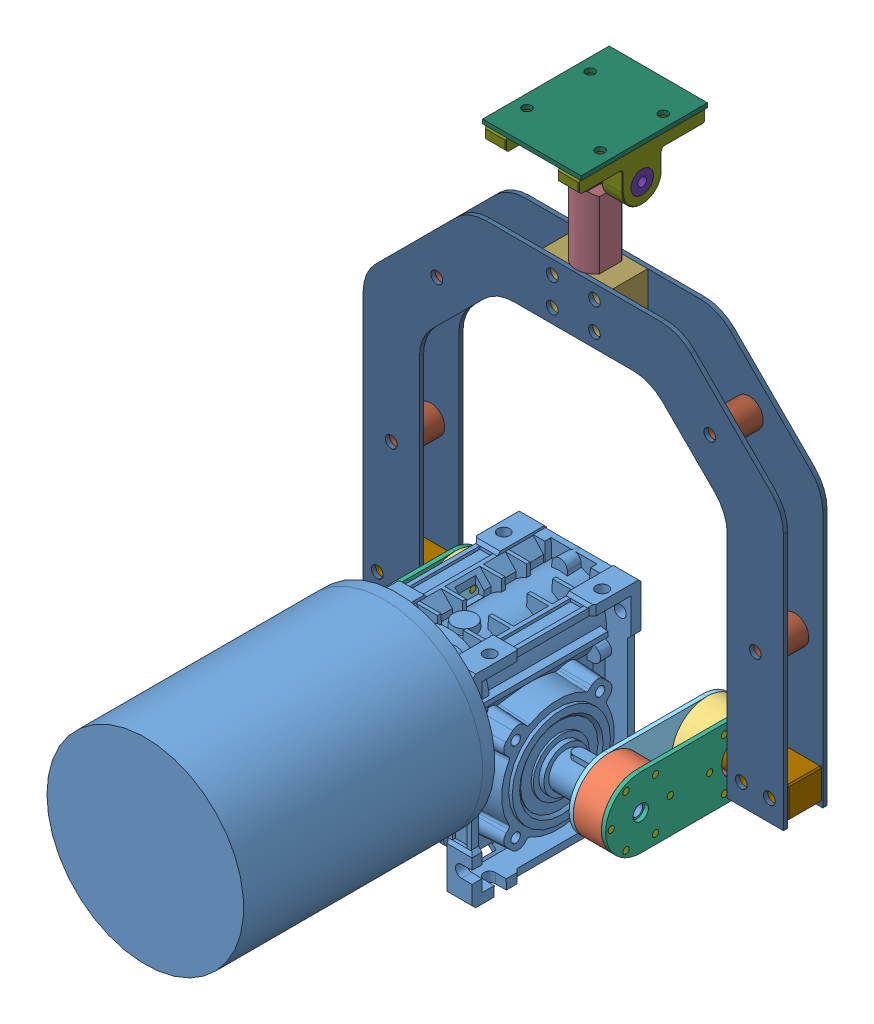
SolidWorks assembly motor con viela, configuration Predeterminado. Lengths in mm.
Overall size (299 406 365).
58 component instances, 18 part files, 42 mates.
Components (placement in the parent):
- reductor con motor-1: reductor con motor [Predeterminado] at origin size (199 179.97 310)
- manivela-1: manivela [Predeterminado] at (79.5 -50 -64) x (0 0 -1) z (1 0 0) size (120 50 26)
  - cople flecha-1: cople flecha [Predeterminado] at origin size (50 50 20)
  - cople rodamiento-1: cople rodamiento [Predeterminado] at (70 0 0) size (50 50 20)
  - rodameitno falso-1: rodameitno falso [Predeterminado] at (70 0 6) size (35 35 14)
  - placa manivela-2: placa manivela [Predeterminado] at (0 0 -3) size (120 50 3)
  - placa manivela 2-3: placa manivela 2 [Predeterminado] at (0 0 20) size (120 50 3)
  - tornillo falso-2: tornillo falso [Predeterminado] at (-10.5 18.1865 23) x (-0.923728 -0.383049 0) z (0 0 -1) size (4.3 4.3 26)
  - tornillo falso-3: tornillo falso [Predeterminado] at (-21 0 23) x (-0.923728 -0.383049 0) z (0 0 -1) size (4.3 4.3 26)
  - tornillo falso-4: tornillo falso [Predeterminado] at (-10.5 -18.1865 23) x (-0.923728 -0.383049 0) z (0 0 -1) size (4.3 4.3 26)
  - tornillo falso-5: tornillo falso [Predeterminado] at (10.5 -18.1865 23) x (-0.923728 -0.383049 0) z (0 0 -1) size (4.3 4.3 26)
  - tornillo falso-6: tornillo falso [Predeterminado] at (21 0 23) x (-0.923728 -0.383049 0) z (0 0 -1) size (4.3 4.3 26)
  - tornillo falso-7: tornillo falso [Predeterminado] at (10.5 18.1865 23) x (-0.923728 -0.383049 0) z (0 0 -1) size (4.3 4.3 26)
  - tornillo falso-8: tornillo falso [Predeterminado] at (59.5 18.1865 23) x (-0.923728 -0.383049 0) z (0 0 -1) size (4.3 4.3 26)
  - tornillo falso-9: tornillo falso [Predeterminado] at (49 0 23) x (-0.923728 -0.383049 0) z (0 0 -1) size (4.3 4.3 26)
  - tornillo falso-10: tornillo falso [Predeterminado] at (80.5 18.1865 23) x (-0.923728 -0.383049 0) z (0 0 -1) size (4.3 4.3 26)
  - tornillo falso-11: tornillo falso [Predeterminado] at (59.5 -18.1865 23) x (-0.923728 -0.383049 0) z (0 0 -1) size (4.3 4.3 26)
  - tornillo falso-12: tornillo falso [Predeterminado] at (80.5 -18.1865 23) x (-0.923728 -0.383049 0) z (0 0 -1) size (4.3 4.3 26)
  - tornillo falso-13: tornillo falso [Predeterminado] at (91 0 23) x (-0.923728 -0.383049 0) z (0 0 -1) size (4.3 4.3 26)
  - anillo manivela-1: anillo manivela [Predeterminado] at (70 0 0) x (0.999916 -0.012929 0) z (0 0 1) size (35 35 6)
- manivela derecha-1: manivela derecha [Predeterminado] at (-99.5 -50 -64) x (0 0 -1) z (1 0 0) size (120 50 26)
  - cople flecha-1: cople flecha [Predeterminado] at origin size (50 50 20)
  - cople rodamiento-1: cople rodamiento [Predeterminado] at (70 0 0) size (50 50 20)
  - rodameitno falso-1: rodameitno falso [Predeterminado] at (70 0 0) size (35 35 14)
  - placa manivela 2-4: placa manivela 2 [Predeterminado] at (0 0 -3) size (120 50 3)
  - placa manivela-3: placa manivela [Predeterminado] at (0 0 20) size (120 50 3)
  - tornillo falso-2: tornillo falso [Predeterminado] at (-10.5 18.1865 23) x (-0.923728 -0.383049 0) z (0 0 -1) size (4.3 4.3 26)
  - tornillo falso-3: tornillo falso [Predeterminado] at (-21 0 23) x (-0.923728 -0.383049 0) z (0 0 -1) size (4.3 4.3 26)
  - tornillo falso-4: tornillo falso [Predeterminado] at (-10.5 -18.1865 23) x (-0.923728 -0.383049 0) z (0 0 -1) size (4.3 4.3 26)
  - tornillo falso-5: tornillo falso [Predeterminado] at (10.5 -18.1865 23) x (-0.923728 -0.383049 0) z (0 0 -1) size (4.3 4.3 26)
  - tornillo falso-6: tornillo falso [Predeterminado] at (21 0 23) x (-0.923728 -0.383049 0) z (0 0 -1) size (4.3 4.3 26)
  - tornillo falso-7: tornillo falso [Predeterminado] at (10.5 18.1865 23) x (-0.923728 -0.383049 0) z (0 0 -1) size (4.3 4.3 26)
  - tornillo falso-8: tornillo falso [Predeterminado] at (59.5 18.1865 23) x (-0.923728 -0.383049 0) z (0 0 -1) size (4.3 4.3 26)
  - tornillo falso-9: tornillo falso [Predeterminado] at (49 0 23) x (-0.923728 -0.383049 0) z (0 0 -1) size (4.3 4.3 26)
  - tornillo falso-10: tornillo falso [Predeterminado] at (80.5 18.1865 23) x (-0.923728 -0.383049 0) z (0 0 -1) size (4.3 4.3 26)
  - tornillo falso-11: tornillo falso [Predeterminado] at (59.5 -18.1865 23) x (-0.923728 -0.383049 0) z (0 0 -1) size (4.3 4.3 26)
  - tornillo falso-12: tornillo falso [Predeterminado] at (80.5 -18.1865 23) x (-0.923728 -0.383049 0) z (0 0 -1) size (4.3 4.3 26)
  - tornillo falso-13: tornillo falso [Predeterminado] at (91 0 23) x (-0.923728 -0.383049 0) z (0 0 -1) size (4.3 4.3 26)
  - anillo manivela-1: anillo manivela [Predeterminado] at (70 0 14) x (0.996967 0.077829 0) z (0 0 1) size (35 35 6)
- pin de manivela-1: pin de manivela [Predeterminado] at (74.5 -50 -134) x (-1 0 0) z (0 0 -1) size (75 22 25)
- pin de manivela-2: pin de manivela [Predeterminado] at (-74.5 -50 -134) size (75 22 25)
- arco-2: arco [Predeterminado] at (0 -65 -149.5) size (299 270 3)
- virlo-1: virlo [Predeterminado] at (129.5 35.125 -146.5) x (-0.745023 -0.667039 0) z (0 0 1) size (20 20 25)
- virlo-2: virlo [Predeterminado] at (-129.5 35.125 -146.5) x (-0.745023 -0.667039 0) z (0 0 1) size (20 20 25)
- virlo-3: virlo [Predeterminado] at (97.125 152.625 -146.5) x (-0.745023 -0.667039 0) z (0 0 1) size (20 20 25)
- virlo-4: virlo [Predeterminado] at (-97.125 152.625 -146.5) x (-0.797624 -0.603155 0) z (0 0 1) size (20 20 25)
- arco-3: arco [Predeterminado] at (0 -65 -121.5) size (299 270 3)
- bloque-1: bloque [Predeterminado] at (0 185 -134) size (50 40 25)
- Rotula de esfera-1: Rotula de esfera [M16] at (0 205 -134) x (0 0 1) z (-1 0 0) size (38 83 22)
  - rotula-1: rotula [M16] at origin size (38 83 22)
  - esfera-1: esfera [M16] at (0 64 0) size (30 30 21)
- soperte superior-1: soperte superior [Predeterminado] at (0 293 -134) size (70 41 90)
  - placa superior-1: placa superior [Predeterminado] at origin size (70 3 90)
  - soporte superior-1: soporte superior [Predeterminado] at (-26 -24 0) x (0 0 1) z (-1 0 0) size (90 38 15)
  - soporte superior-2: soporte superior [Predeterminado] at (26 -24 0) x (0 0 1) z (-1 0 0) size (90 38 15)
- pin superior-1: pin superior [Predeterminado] at (0 269 -134) size (67 16 16)
- virlo superior-1: virlo superior [Predeterminado] at (10.5 269 -134) x (0 0.431758 -0.90199) z (1 0 0) size (22 22 8)
- virlo superior-2: virlo superior [Predeterminado] at (-18.5 269 -134) x (0 0.14992 -0.988698) z (1 0 0) size (22 22 8)
Mates (geometry in assembly coordinates):
- Concéntrica1: concentric aligned: cylinder of reductor con motor-1 through (49.5 -50 -64) axis (1 0 0) radius 12.5; cylinder of manivela-1/cople flecha-1 through (79.5 -50 -64) axis (1 0 0) radius 13
- Coincidente1: coincident anti-aligned: plane of reductor con motor-1 through (99.5 -50 -64) normal (1 0 0); plane of manivela-1/placa manivela 2-3 through (99.5 -50 -64) normal (-1 0 0)
- Paralelo1: parallel anti-aligned: plane of reductor con motor-1 through (54.5 -34.5 -68) normal (0 1 0); plane of manivela-1/placa manivela-2 through (76.5 -33.7 -68) normal (0 -1 0)
- Concéntrica2: concentric anti-aligned: cylinder of reductor con motor-1 through (-49.5 -50 -64) axis (-1 0 0) radius 12.5; cylinder of manivela derecha-1/cople flecha-1 through (-99.5 -50 -64) axis (1 0 0) radius 13
- Coincidente3: coincident anti-aligned: plane of reductor con motor-1 through (-99.5 -50 -64) normal (-1 0 0); plane of manivela derecha-1/placa manivela 2-4 through (-99.5 -50 -64) normal (1 0 0)
- Paralelo2: parallel anti-aligned: plane of reductor con motor-1 through (-54.5 -34.5 -68) normal (0 1 0); plane of manivela derecha-1/placa manivela-3 through (-79.5 -33.7 -68) normal (0 -1 0)
- Concéntrica3: concentric anti-aligned: cylinder of manivela-1/rodameitno falso-1 through (99.5 -50 -134) axis (-1 0 0) radius 7.5; cylinder of pin de manivela-1 through (149.5 -50 -134) axis (1 0 0) radius 7.5
- Coincidente5: coincident anti-aligned: plane of manivela-1/rodameitno falso-1 through (99.5 -50 -134) normal (1 0 0); plane of pin de manivela-1 through (99.5 -42.5 -134) normal (-1 0 0)
- Concéntrica4: concentric aligned: cylinder of manivela derecha-1/rodameitno falso-1 through (-85.5 -50 -134) axis (-1 0 0) radius 7.5; cylinder of pin de manivela-2 through (-149.5 -50 -134) axis (-1 0 0) radius 7.5
- Coincidente6: coincident aligned: plane of manivela derecha-1/rodameitno falso-1 through (-99.5 -50 -134) normal (-1 0 0); circle of pin de manivela-2
- Coincidente10: coincident anti-aligned: plane of pin de manivela-1 through (149.5 -61 -146.5) normal (0 0 -1); plane of arco-2 through (119.5 117.8236 -146.5) normal (0 0 1)
- Concéntrica8: concentric anti-aligned: cylinder of pin de manivela-1 through (119.5 -50 -146.5) axis (0 0 -1) radius 4.2; cylinder of arco-2 through (119.5 -50 -146.5) axis (0 0 1) radius 4.2
- Concéntrica9: concentric anti-aligned: cylinder of pin de manivela-1 through (139.5 -50 -146.5) axis (0 0 -1) radius 4.2; cylinder of arco-2 through (139.5 -50 -146.5) axis (0 0 1) radius 4.2
- Concéntrica10: concentric aligned: cylinder of pin de manivela-2 through (-119.5 -50 -121.5) axis (0 0 1) radius 4.2; cylinder of arco-2 through (-119.5 -50 -146.5) axis (0 0 1) radius 4.2
- Concéntrica11: concentric aligned: cylinder of pin de manivela-2 through (-139.5 -50 -121.5) axis (0 0 1) radius 4.2; cylinder of arco-2 through (-139.5 -50 -146.5) axis (0 0 1) radius 4.2
- Coincidente12: coincident anti-aligned: plane of arco-2 through (119.5 117.8236 -146.5) normal (0 0 1); plane of virlo-1 through (129.5 35.125 -146.5) normal (0 0 -1)
- Concéntrica12: concentric aligned: cylinder of arco-2 through (129.5 35.125 -146.5) axis (0 0 1) radius 4.2; cylinder of virlo-1 through (129.5 35.125 -121.5) axis (0 0 1) radius 4.2
- Concéntrica131: concentric aligned: cylinder of arco-2 through (97.125 152.625 -146.5) axis (0 0 1) radius 4.2; cylinder of virlo-3 through (97.125 152.625 -121.5) axis (0 0 1) radius 4.2
- Coincidente13: coincident anti-aligned: plane of arco-2 through (119.5 117.8236 -146.5) normal (0 0 1); plane of virlo-3 through (97.125 152.625 -146.5) normal (0 0 -1)
- Concéntrica141: concentric aligned: cylinder of arco-2 through (-97.125 152.625 -146.5) axis (0 0 1) radius 4.2; cylinder of virlo-4 through (-97.125 152.625 -121.5) axis (0 0 1) radius 4.2
- Coincidente14: coincident anti-aligned: plane of arco-2 through (119.5 117.8236 -146.5) normal (0 0 1); plane of virlo-4 through (-97.125 152.625 -146.5) normal (0 0 -1)
- Coincidente15: coincident anti-aligned: plane of arco-2 through (119.5 117.8236 -146.5) normal (0 0 1); plane of virlo-2 through (-129.5 35.125 -146.5) normal (0 0 -1)
- Concéntrica15: concentric aligned: cylinder of arco-2 through (-129.5 35.125 -146.5) axis (0 0 1) radius 4.2; cylinder of virlo-2 through (-129.5 35.125 -121.5) axis (0 0 1) radius 4.2
- Coincidente16: coincident anti-aligned: plane of pin de manivela-2 through (-149.5 -61 -121.5) normal (0 0 1); plane of arco-3 through (119.5 117.8236 -121.5) normal (0 0 -1)
- Concéntrica16: concentric aligned: cylinder of virlo-4 through (-97.125 152.625 -121.5) axis (0 0 1) radius 4.2; cylinder of arco-3 through (-97.125 152.625 -118.5) axis (0 0 1) radius 4.2
- Concéntrica17: concentric aligned: cylinder of virlo-1 through (129.5 35.125 -121.5) axis (0 0 1) radius 4.2; cylinder of arco-3 through (129.5 35.125 -118.5) axis (0 0 1) radius 4.2
- Coincidente17: coincident anti-aligned: plane of arco-3 through (119.5 117.8236 -121.5) normal (0 0 -1); plane of bloque-1 through (0 185 -121.5) normal (0 0 1)
- Concéntrica18: concentric aligned: cylinder of arco-3 through (-15 195 -118.5) axis (0 0 1) radius 4.2; cylinder of bloque-1 through (-15 195 -121.5) axis (0 0 1) radius 4.2
- Concéntrica19: concentric aligned: cylinder of arco-3 through (15 175 -118.5) axis (0 0 1) radius 4.2; cylinder of bloque-1 through (15 175 -121.5) axis (0 0 1) radius 4.2
- Concéntrica20: concentric anti-aligned: cylinder of bloque-1 through (0 205 -134) axis (0 1 0) radius 8.5; cylinder of Rotula de esfera-1/rotula-1 through (0 205 -134) axis (0 -1 0) radius 8.75
- Coincidente18: coincident anti-aligned: plane of bloque-1 through (-25 205 -121.5) normal (0 1 0); plane of Rotula de esfera-1/rotula-1 through (0 205 -134) normal (0 -1 0)
- Perpendicular1: perpendicular: plane of arco-2 through (119.5 117.8236 -149.5) normal (0 0 -1); plane of Rotula de esfera-1/rotula-1 through (11 205 -153) normal (1 0 0)
- Concéntrica21: concentric anti-aligned: cylinder of Rotula de esfera-1/esfera-1 through (15 269 -134) axis (-1 0 0) radius 8; cylinder of soperte superior-1/soporte superior-2 through (18.5 269 -134) axis (1 0 0) radius 8
- Concéntrica22: concentric anti-aligned: cylinder of soperte superior-1/soporte superior-2 through (18.5 269 -134) axis (1 0 0) radius 8; cylinder of pin superior-1 through (33.5 269 -134) axis (-1 0 0) radius 8
- Coincidente20: coincident aligned: plane of soperte superior-1/soporte superior-2 through (33.5 269 -134) normal (1 0 0); plane of pin superior-1 through (33.5 269 -134) normal (1 0 0)
- Concéntrica23: concentric aligned: cylinder of pin superior-1 through (33.5 269 -134) axis (-1 0 0) radius 8; cylinder of virlo superior-1 through (18.5 269 -134) axis (-1 0 0) radius 8
- Concéntrica24: concentric aligned: cylinder of pin superior-1 through (33.5 269 -134) axis (-1 0 0) radius 8; cylinder of virlo superior-2 through (-10.5 269 -134) axis (-1 0 0) radius 8
- Paralelo4: parallel aligned: plane of arco-3 through (119.5 117.8236 -118.5) normal (0 0 1)
- Paralelo5: parallel aligned: plane of soperte superior-1/placa superior-1 through (0 296 -134) normal (0 1 0)
- Coincidente21: coincident anti-aligned: plane of Rotula de esfera-1/esfera-1 through (10.5 258.2879 -149) normal (1 0 0); plane of virlo superior-1 through (10.5 269 -134) normal (-1 0 0)
- Coincidente22: coincident anti-aligned: plane of Rotula de esfera-1/esfera-1 through (-10.5 258.2879 -149) normal (-1 0 0); plane of virlo superior-2 through (-10.5 269 -134) normal (1 0 0)
- Coincidente23: coincident anti-aligned: plane of soperte superior-1/soporte superior-1 through (-18.5 269 -134) normal (1 0 0); plane of virlo superior-2 through (-18.5 269 -134) normal (-1 0 0)
